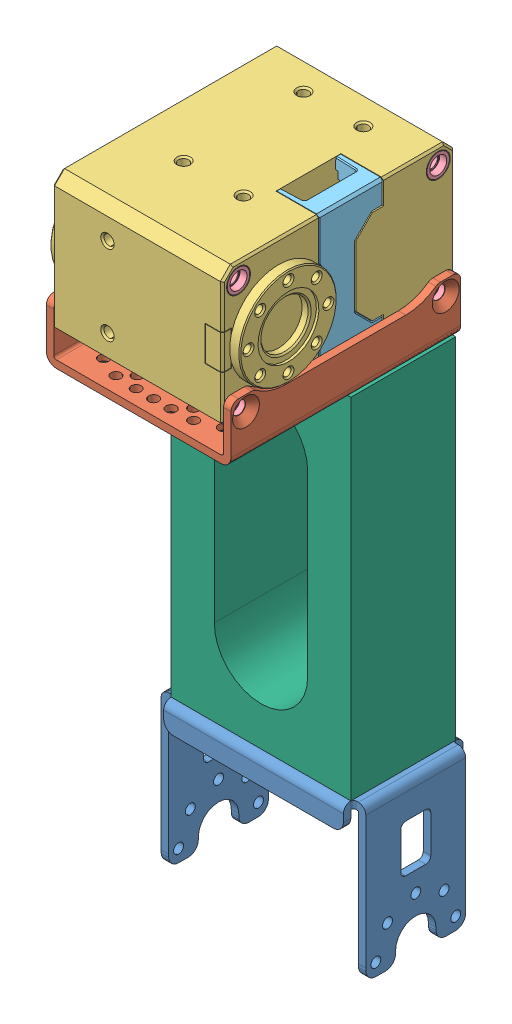
SolidWorks assembly link3_2, configuration 기본. Lengths in mm.
Overall size (43.9 134.25 47.25).
14 component instances, 6 part files, 9 mates.
Components (placement in the parent):
- fr12_h101-1: fr12_h101 [기본] at (-2.6588 -12.6867 41) size (41 30.5 24)
- fr12_s101-1: fr12_s101 [기본] at (-2.6588 104.8133 65) x (1 0 0) z (0 -1 0) size (37 46 11.5)
- x-430_idle-2: x-430_idle [기본] at (-2.6588 104.8133 65) x (0 -1 0) z (-1 0 0) size (28.5 46.5 42.4)
  - X-430_IDLE-1: X-430_IDLE [기본] at origin size (28.5 46.5 42.4)
  - X-430_SPACER_RING-1: X-430_SPACER_RING [기본] at (11 8 14.2) x (-1 0 0) z (0 1 0) size (4.8 2.8 4.8)
  - X-430_SPACER_RING-2: X-430_SPACER_RING [기본] at (-11 8 14.2) x (-1 0 0) z (0 1 0) size (4.8 2.8 4.8)
  - X-430_SPACER_RING-3: X-430_SPACER_RING [기본] at (11 -32 14.2) x (-1 0 0) z (0 1 0) size (4.8 2.8 4.8)
  - X-430_SPACER_RING-4: X-430_SPACER_RING [기본] at (-11 -32 14.2) x (-1 0 0) z (0 1 0) size (4.8 2.8 4.8)
  - X-430_SPACER_RING-5: X-430_SPACER_RING [기본] at (-11 8 -14.2) x (1 0 0) z (0 1 0) size (4.8 2.8 4.8)
  - X-430_SPACER_RING-6: X-430_SPACER_RING [기본] at (11 8 -14.2) x (1 0 0) z (0 1 0) size (4.8 2.8 4.8)
  - X-430_SPACER_RING-7: X-430_SPACER_RING [기본] at (-11 -32 -14.2) x (1 0 0) z (0 1 0) size (4.8 2.8 4.8)
  - X-430_SPACER_RING-8: X-430_SPACER_RING [기본] at (11 -32 -14.2) x (1 0 0) z (0 1 0) size (4.8 2.8 4.8)
  - X-430_CVR_CABLE-1: X-430_CVR_CABLE [기본] at origin size (28.5 12.8 8.8)
- linkframe1_2-1: linkframe1_2 [기본] at (-2.6588 15.3133 41) x (1 0 0) z (0 1 0) size (36 21 70)
Mates (geometry in assembly coordinates):
- 동심8: concentric anti-aligned: circle of fr12_s101-1; circle of x-430_idle-2/X-430_SPACER_RING-1
- 동심9: concentric anti-aligned: circle of fr12_s101-1; circle of x-430_idle-2/X-430_SPACER_RING-3
- 너비1: width anti-aligned: plane of fr12_s101-1 through (-19.6588 87.3133 30) normal (1 0 0); plane of fr12_s101-1 through (14.3412 96.8133 30) normal (-1 0 0); plane of x-430_idle-2/X-430_IDLE-1 through (-19.6588 104.8133 65) normal (-1 0 0); plane of x-430_idle-2/X-430_CVR_CABLE-1 through (14.3412 104.8133 65) normal (1 0 0)
- Concentric1: concentric anti-aligned: circle of fr12_h101-1; circle of linkframe1_2-1
- Concentric2: concentric aligned: circle of fr12_h101-1; circle of linkframe1_2-1
- Coincident1: coincident anti-aligned: plane of fr12_h101-1 through (-21.6588 15.3133 51) normal (0 1 0); plane of linkframe1_2-1 through (-2.6588 15.3133 41) normal (0 -1 0)
- Concentric3: concentric aligned: circle of fr12_s101-1; circle of linkframe1_2-1
- Concentric4: concentric aligned: circle of fr12_s101-1; circle of linkframe1_2-1
- Coincident2: coincident anti-aligned: plane of fr12_s101-1 through (13.8412 85.3133 30) normal (0 -1 0); plane of linkframe1_2-1 through (-2.6588 85.3133 41) normal (0 1 0)
